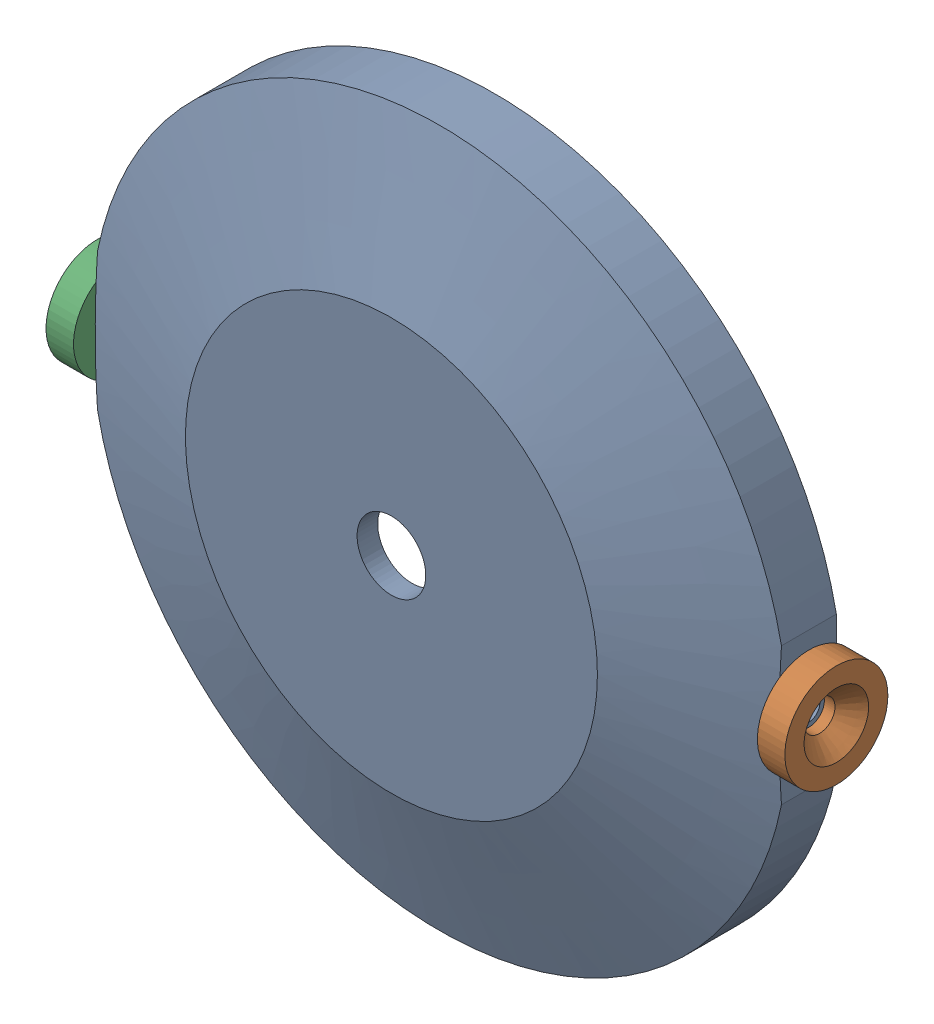
SolidWorks assembly engine_sensor, configuration Default. Lengths in mm.
Overall size (107.6 101.6 20.55).
3 component instances, 2 part files, 4 mates.
Components (placement in the parent):
- engine_Ring-1: engine_Ring [Default] at (-8.2696 -4.5437 14.9506) size (99.6 101.6 15)
- magnet-1: magnet [Default] at (45.5304 -4.5437 3.9506) x (0 -0.124309 -0.992244) z (1 0 0) size (15 15 4)
- magnet-2: magnet [Default] at (-62.0696 -4.5437 3.9506) x (0 0.94434 -0.328972) z (-1 0 0) size (15 15 4)
Mates (geometry in assembly coordinates):
- Concentric1: concentric: circle of engine_Ring-1; cylinder of magnet-1 through (41.5304 -4.5437 3.9506) axis (1 0 0) radius 7.5
- Coincident1: coincident aligned: plane of engine_Ring-1 through (41.5304 -4.5437 14.9506) normal (1 0 0); circle of magnet-1
- Coincident2: coincident: plane of engine_Ring-1 through (-58.0696 -4.5437 14.9506) normal (-1 0 0); circle of magnet-2
- Concentric2: concentric aligned: cylinder of engine_Ring-1 through (-58.0696 -4.5437 3.9506) axis (-1 0 0) radius 1.5875; cylinder of magnet-2 through (-62.0696 -6.5149 -16.0632) axis (-1 0 0) radius 2.25
